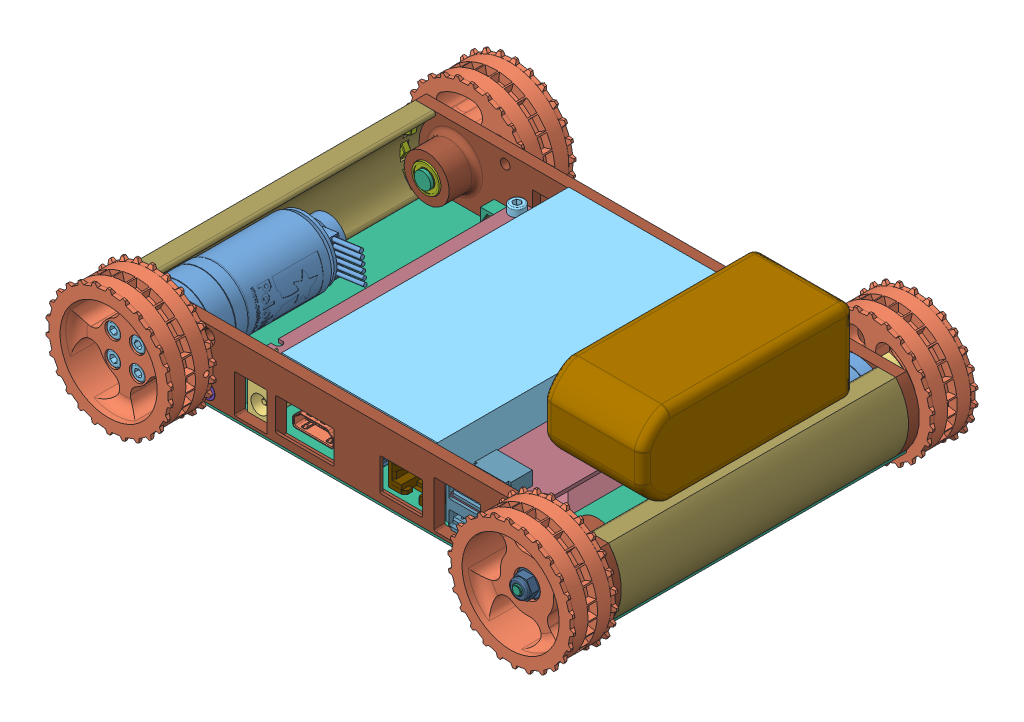
SolidWorks assembly base, configuration Default. Lengths in mm.
Overall size (209.85 74.01 148).
100 component instances, 27 part files, 139 mates.
Components (placement in the parent):
- wheels-1: wheels [Right] at origin size (207.65 62.92 81)
  - wheel-powered-1: wheel-powered [Default] at (0.6984 4.2216 -21.5) x (0.139173 -0.990268 0) z (0 0 1) size (51.92 51.74 81)
    - wheel-motor-1: wheel-motor [Default] at (-36.8745 16.797 -18.375) x (0.990268 -0.139173 0) z (0 0 1) size (25 32.85 72)
    - wheel-body-1: wheel-body [Powered Visual] at (-6.3 12.5 5) x (0.990268 -0.139173 0) z (0 0 1) size (46 45.78 16.5)
    - wheel-motor-mount-1: wheel-motor-mount [Default] at (-6.3 12.5 5) x (0.990268 -0.139173 0) z (-0.139173 -0.990268 0) size (19 5 19)
    - M2.5-6mm-scrub-1: M2.5-6mm-scrub [Default] at (-6.0912 13.9854 7.5) x (0.990268 -0.139173 0) z (0 0 1) size (3.05 6.18 3.38)
    - M3-8mm-bolt-1: M3-8mm-bolt [Default] at (-10.1215 17.5713 15.2) x (1 0 0) z (0 1 0) size (5.5 10.77 5.5)
    - M3-8mm-bolt-2: M3-8mm-bolt [Default] at (-1.2287 16.3215 15.2) x (0.987351 0.158553 0) z (-0.158553 0.987351 0) size (5.5 10.77 5.5)
    - M3-8mm-bolt-4: M3-8mm-bolt [Default] at (-11.3713 8.6785 15.2) x (0.959125 0.282984 0) z (-0.282984 0.959125 0) size (5.5 10.77 5.5)
    - M3-8mm-bolt-6: M3-8mm-bolt [Default] at (-2.4785 7.4287 15.2) x (0.928571 0.371154 0) z (-0.371154 0.928571 0) size (5.5 10.77 5.5)
  - wheel-free-1: wheel-free [Default] at (159.2 12.2 -33.24) x (-0.859884 -0.510489 0) z (0 0 1) size (45.78 46 33.24)
    - wheel-free-shaft-1: wheel-free-shaft [Default] x (1 0 0) z (0 -1 0) size (6 31.32 6)
    - wheel-free-bearing-1: wheel-free-bearing [Default] at (0 0 5.07) x (1 0 0) z (0 1 0) size (10 3.97 10)
    - wheel-free-bearing-2: wheel-free-bearing [Default] at (0 0 15.74) x (0.774434 0.632655 0) z (-0.632655 0.774434 0) size (10 3.97 10)
    - wheel-free-spacer-1: wheel-free-spacer [Default] at (0 0 16.74) x (0.90405 -0.427427 0) z (0.427427 0.90405 0) size (7 1 7)
    - wheel-free-pin-1: wheel-free-pin [Default] at (0 -4.75 18.2) x (0.907276 0 -0.420536) z (0.420536 0 0.907276) size (2 9.5 2)
    - wheel-body-1: wheel-body [Free] at (0 0 16.74) x (0 -1 0) z (0 0 1) size (46 45.78 16.5)
    - M4-nut-1: M4-nut [Default] at (0 0 25.24) x (1 0 0) z (0 -1 0) size (9.3 5.45 9.3)
  - side-plate-1: side-plate [Right] at (12.2 43.075 -21.5) x (0 -1 0) z (0 0 1) size (25 185 14.2)
- wheels-2: wheels [Default] at (171.4 0 -148) x (-1 0 0) z (0 0 -1) size (207.65 62.92 81)
  - wheel-powered-1: wheel-powered [Default] at (0.6984 4.2216 -21.5) x (0.139173 -0.990268 0) z (0 0 1) size (51.92 51.74 81)
    - wheel-motor-1: wheel-motor [Default] at (-36.8745 16.797 -18.375) x (0.990268 -0.139173 0) z (0 0 1) size (25 32.85 72)
    - wheel-body-1: wheel-body [Powered Visual] at (-6.3 12.5 5) x (0.990268 -0.139173 0) z (0 0 1) size (46 45.78 16.5)
    - wheel-motor-mount-1: wheel-motor-mount [Default] at (-6.3 12.5 5) x (0.990268 -0.139173 0) z (-0.139173 -0.990268 0) size (19 5 19)
    - M2.5-6mm-scrub-1: M2.5-6mm-scrub [Default] at (-6.0912 13.9854 7.5) x (0.990268 -0.139173 0) z (0 0 1) size (3.05 6.18 3.38)
    - M3-8mm-bolt-1: M3-8mm-bolt [Default] at (-10.1215 17.5713 15.2) x (1 0 0) z (0 1 0) size (5.5 10.77 5.5)
    - M3-8mm-bolt-2: M3-8mm-bolt [Default] at (-1.2287 16.3215 15.2) x (0.987351 0.158553 0) z (-0.158553 0.987351 0) size (5.5 10.77 5.5)
    - M3-8mm-bolt-4: M3-8mm-bolt [Default] at (-11.3713 8.6785 15.2) x (0.959125 0.282984 0) z (-0.282984 0.959125 0) size (5.5 10.77 5.5)
    - M3-8mm-bolt-6: M3-8mm-bolt [Default] at (-2.4785 7.4287 15.2) x (0.928571 0.371154 0) z (-0.371154 0.928571 0) size (5.5 10.77 5.5)
  - wheel-free-1: wheel-free [Default] at (159.2 12.2 -33.24) x (-0.859884 -0.510489 0) z (0 0 1) size (45.78 46 33.24)
    - wheel-free-shaft-1: wheel-free-shaft [Default] x (1 0 0) z (0 -1 0) size (6 31.32 6)
    - wheel-free-bearing-1: wheel-free-bearing [Default] at (0 0 5.07) x (1 0 0) z (0 1 0) size (10 3.97 10)
    - wheel-free-bearing-2: wheel-free-bearing [Default] at (0 0 15.74) x (0.774434 0.632655 0) z (-0.632655 0.774434 0) size (10 3.97 10)
    - wheel-free-spacer-1: wheel-free-spacer [Default] at (0 0 16.74) x (0.90405 -0.427427 0) z (0.427427 0.90405 0) size (7 1 7)
    - wheel-free-pin-1: wheel-free-pin [Default] at (0 -4.75 18.2) x (0.907276 0 -0.420536) z (0.420536 0 0.907276) size (2 9.5 2)
    - wheel-body-1: wheel-body [Free] at (0 0 16.74) x (0 -1 0) z (0 0 1) size (46 45.78 16.5)
    - M4-nut-1: M4-nut [Default] at (0 0 25.24) x (1 0 0) z (0 -1 0) size (9.3 5.45 9.3)
  - side-plate-1: side-plate [Default] at (12.2 43.075 -21.5) x (0 -1 0) z (0 0 1) size (25 185 14.2)
- base-end-1: base-end [Default] at (159.2 43.075 -126.5) x (0 1 0) z (0 0 1) size (25 12.02 105)
- base-end-2: base-end [Default] at (12.2 -18.675 -126.5) x (0 -1 0) z (0 0 1) size (25 12.02 105)
- computer-2: computer [Default] at (85.7 11.95 -74) x (0 0 -1) z (-1 0 0) size (112.78 24.5 100)
  - computer-pcb-1: computer-pcb [Default] at origin size (109 1.25 100)
  - usb-a-double-1: usb-a-double [Default] at (47.745 -3.9 -36.45) x (0 0 -1) z (1 0 0) size (14.6 16.2 17.65)
  - audio-jack-1: audio-jack [Défaut] at (56.5 1.25 -19.25) x (-1 0 0) z (0 0 -1) size (15 6 12)
    - mj1-3510-smt_01-1: mj1-3510-smt_01 [Défaut] at origin size (15 6 10.5)
    - mj1-3510-smt_02-1: mj1-3510-smt_02 [Défaut] at origin size (1 0.25 2.25)
    - mj1-3510-smt_03-1: mj1-3510-smt_03 [Défaut] at origin size (1.5 0.25 2.25)
  - usb-a-double-2: usb-a-double [Default] at (-44.375 -3.9 -36.45) x (0 0 1) z (-1 0 0) size (14.6 16.2 17.65)
  - ethernet-jack-1: ethernet-jack [Default] at (-45.057 -4.375 -15.993) x (0 0 1) z (-1 0 0) size (15.99 16.55 21.05)
  - mini-display-port-1: mini-display-port [Default] at (-52.62 -3.25 -3.4195) x (0 0 1) z (-1 0 0) size (9.11 10.68 14.44)
  - hdmi-1: hdmi [Default] at (-44.9 4.575 19.5) x (0 0 1) z (-1 0 0) size (16.2 8 9.9)
  - power-jack-1: power-jack [Default] at (-45.5 -0.05 39) x (0 0 -1) z (1 0 0) size (9.4 14.5 14.4)
  - computer-top-components-1: computer-top-components [Default] at (3.5 1.25 -0.5) size (74 10 95)
  - computer-bottom-components-1: computer-bottom-components [Default] at (0 -13.25 3.227) x (0 0 1) z (-1 0 0) size (57 13.25 105)
- bottom-plate-1: bottom-plate [Default] at (12.2 -0.3 -21.5) x (0 0 -1) z (0 -1 0) size (113 175.62 11.8)
- M3-nut-1: M3-nut [Default] at (174.2 12.2 -27.85) x (-0.866025 0.5 0) z (0.5 0.866025 0) size (5.5 2.61 6.23)
- M3-flathead-bolt-1: M3-flathead-bolt [Default] at (174.2 12.2 -17.5) x (0.99991 -0.013402 0) z (0.013402 0.99991 0) size (5.5 10.3 5.5)
- M3-nut-2: M3-nut [Default] at (171.4873 20.8036 -27.85) x (-0.996195 -0.087156 0) z (-0.087156 0.996195 0) size (5.5 2.61 6.23)
- M3-nut-4: M3-nut [Default] at (171.4873 3.5964 -27.85) x (-0.422618 0.906308 0) z (0.906308 0.422618 0) size (5.5 2.61 6.23)
- M3-nut-6: M3-nut [Default] at (171.4873 20.8036 -120.15) x (0.422618 0.906308 0) z (-0.906308 0.422618 0) size (5.5 2.61 6.23)
- M3-nut-8: M3-nut [Default] at (174.2 12.2 -120.15) x (0.866025 0.5 0) z (-0.5 0.866025 0) size (5.5 2.61 6.23)
- M3-nut-10: M3-nut [Default] at (171.4873 3.5964 -120.15) x (0.996195 -0.087156 0) z (0.087156 0.996195 0) size (5.5 2.61 6.23)
- M3-nut-12: M3-nut [Default] at (-0.0873 20.8036 -120.15) x (0.996195 -0.087156 0) z (0.087156 0.996195 0) size (5.5 2.61 6.23)
- M3-nut-14: M3-nut [Default] at (-2.8 12.2 -120.15) x (0.866025 0.5 0) z (-0.5 0.866025 0) size (5.5 2.61 6.23)
- M3-nut-16: M3-nut [Default] at (-0.0873 3.5964 -120.15) x (0.422618 0.906308 0) z (-0.906308 0.422618 0) size (5.5 2.61 6.23)
- M3-nut-18: M3-nut [Default] at (-0.0873 20.8036 -27.85) x (-0.422618 0.906308 0) z (0.906308 0.422618 0) size (5.5 2.61 6.23)
- M3-nut-20: M3-nut [Default] at (-2.8 12.2 -27.85) x (-0.866025 0.5 0) z (0.5 0.866025 0) size (5.5 2.61 6.23)
- M3-nut-22: M3-nut [Default] at (-0.0873 3.5964 -27.85) x (-0.996195 -0.087156 0) z (-0.087156 0.996195 0) size (5.5 2.61 6.23)
- M3-flathead-bolt-2: M3-flathead-bolt [Default] at (171.4873 20.8036 -17.5) x (0.203723 -0.979029 0) z (0.979029 0.203723 0) size (5.5 10.3 5.5)
- M3-flathead-bolt-4: M3-flathead-bolt [Default] at (171.4873 3.5964 -17.5) x (0.030622 -0.999531 0) z (0.999531 0.030622 0) size (5.5 10.3 5.5)
- M3-flathead-bolt-6: M3-flathead-bolt [Default] at (-0.0873 20.8036 -17.5) x (-0.14341 -0.989663 0) z (0.989663 -0.14341 0) size (5.5 10.3 5.5)
- M3-flathead-bolt-8: M3-flathead-bolt [Default] at (-2.8 12.2 -17.5) x (-0.313085 -0.949725 0) z (0.949725 -0.313085 0) size (5.5 10.3 5.5)
- M3-flathead-bolt-10: M3-flathead-bolt [Default] at (-0.0873 3.5964 -17.5) x (-0.473246 -0.88093 0) z (0.88093 -0.473246 0) size (5.5 10.3 5.5)
- M3-flathead-bolt-12: M3-flathead-bolt [Default] at (-0.0873 20.8036 -130.5) x (0.999996 0.002801 0) z (0.002801 -0.999996 0) size (5.5 10.3 5.5)
- M3-flathead-bolt-14: M3-flathead-bolt [Default] at (-2.8 12.2 -130.5) x (0.995351 0.096317 0) z (0.096317 -0.995351 0) size (5.5 10.3 5.5)
- M3-flathead-bolt-16: M3-flathead-bolt [Default] at (-0.0873 3.5964 -130.5) x (0.972009 0.234946 0) z (0.234946 -0.972009 0) size (5.5 10.3 5.5)
- M3-flathead-bolt-18: M3-flathead-bolt [Default] at (171.4873 20.8036 -130.5) x (0.918511 0.395394 0) z (0.395394 -0.918511 0) size (5.5 10.3 5.5)
- M3-flathead-bolt-20: M3-flathead-bolt [Default] at (174.2 12.2 -130.5) x (0.83874 0.544533 0) z (0.544533 -0.83874 0) size (5.5 10.3 5.5)
- M3-flathead-bolt-22: M3-flathead-bolt [Default] at (171.4873 3.5964 -130.5) x (0.754091 0.65677 0) z (0.65677 -0.754091 0) size (5.5 10.3 5.5)
- M3-flathead-bolt-24: M3-flathead-bolt [Default] at (167.7 12.2 -130.5) x (0.689358 0.724421 0) z (0.724421 -0.689358 0) size (5.5 10.3 5.5)
- M3-flathead-bolt-26: M3-flathead-bolt [Default] at (150.7 12.2 -130.5) x (0.659275 0.751902 0) z (0.751902 -0.659275 0) size (5.5 10.3 5.5)
- M3-flathead-bolt-28: M3-flathead-bolt [Default] at (20.7 12.2 -17.5) x (-0.88093 0.473246 0) z (-0.473246 -0.88093 0) size (5.5 10.3 5.5)
- M3-flathead-bolt-30: M3-flathead-bolt [Default] at (3.7 12.2 -17.5) x (-0.785369 0.619029 0) z (-0.619029 -0.785369 0) size (5.5 10.3 5.5)
- M3-flathead-bolt-32: M3-flathead-bolt [Default] at (30.7 3.5964 -17.5) x (-0.665944 0.746002 0) z (-0.746002 -0.665944 0) size (5.5 10.3 5.5)
- M3-flathead-bolt-34: M3-flathead-bolt [Default] at (140.7 3.5964 -17.5) x (-0.526285 0.850308 0) z (-0.850308 -0.526285 0) size (5.5 10.3 5.5)
- M3-flathead-bolt-36: M3-flathead-bolt [Default] at (30.7 3.5964 -130.5) x (0.918511 0.395394 0) z (0.395394 -0.918511 0) size (5.5 10.3 5.5)
- M3-flathead-bolt-38: M3-flathead-bolt [Default] at (140.7 3.5964 -130.5) x (0.976622 0.214965 0) z (0.214965 -0.976622 0) size (5.5 10.3 5.5)
- M3-nut-24: M3-nut [Default] at (39.05 0.85 -28.7) size (5.5 2.61 6.23)
- M3-nut-25: M3-nut [Default] at (39.05 0.85 -122.5) x (-1 0 0) z (0 0 -1) size (5.5 2.61 6.23)
- M3-nut-27: M3-nut [Default] at (132.35 0.85 -122.5) x (-1 0 0) z (0 0 -1) size (5.5 2.61 6.23)
- M3-nut-29: M3-nut [Default] at (132.35 0.85 -28.7) x (-1 0 0) z (0 0 -1) size (5.5 2.61 6.23)
- M3-8mm-bolt-1: M3-8mm-bolt [Default] at (132.35 14.9 -28.7) x (-0.837169 0 -0.546944) z (-0.546944 0 0.837169) size (5.5 10.77 5.5)
- M3-8mm-bolt-2: M3-8mm-bolt [Default] at (39.05 14.9 -28.7) x (-0.925243 0 -0.379375) z (-0.379375 0 0.925243) size (5.5 10.77 5.5)
- M3-8mm-bolt-3: M3-8mm-bolt [Default] at (39.05 14.9 -122.5) x (-0.985271 0 -0.170998) z (-0.170998 0 0.985271) size (5.5 10.77 5.5)
- M3-8mm-bolt-4: M3-8mm-bolt [Default] at (132.35 14.9 -122.5) x (-0.997902 0 0.064746) z (0.064746 0 0.997902) size (5.5 10.77 5.5)
- M3-nut-30: M3-nut [Default] at (30.7 3.5964 -121.65) x (0 1 0) z (-1 0 0) size (5.5 2.61 6.23)
- M3-nut-31: M3-nut [Default] at (140.7 3.5964 -124) x (0.866025 -0.5 0) z (-0.5 -0.866025 0) size (5.5 2.61 6.23)
- M3-nut-33: M3-nut [Default] at (140.7 3.5964 -26.35) x (0 1 0) z (1 0 0) size (5.5 2.61 6.23)
- M3-nut-35: M3-nut [Default] at (30.7 3.5964 -24) x (-0.866025 -0.5 0) z (0.5 -0.866025 0) size (5.5 2.61 6.23)
- battery-1: battery [Default] at (153.9032 24.7 -74) x (0 0 -1) z (1 0 0) size (77.55 30.1 36.52)
Mates (geometry in assembly coordinates):
- Concentric2: concentric anti-aligned: cylinder of wheels-1/wheel-powered-1/wheel-body-1 through (12.2 12.2 0) axis (0 0 -1) radius 21.75; cylinder of wheels-2/wheel-free-1/wheel-body-1 through (12.2 12.2 -148) axis (0 0 1) radius 21.75
- Concentric3: concentric anti-aligned: cylinder of wheels-1/wheel-free-1/wheel-body-1 through (159.2 12.2 0) axis (0 0 -1) radius 21.75; cylinder of wheels-2/wheel-powered-1/wheel-body-1 through (159.2 12.2 -148) axis (0 0 1) radius 21.75
- InPlace1: in place: plane of ? through (157.2 43.075 -126.5) normal (0 0 1); plane of ? through (0 0 -126.5) normal (0 0 1); moOrthogonalPlaneRef_w of ? through (157.2 43.075 -126.5) normal (0 0 1); plane of ? through (0 0 -126.5) normal (0 1 0); plane of ? through (157.2 43.075 -126.5) normal (0 0 1); plane of ? through (0 0 -126.5) normal (1 0 0); plane of wheels-2/side-plate-1 through (159.2 43.075 -126.5) normal (0 0 1); unknown of base-end-1
- Coincident4: coincident aligned: plane of wheels-2/side-plate-1; plane of base-end-1
- Coincident5: coincident aligned: moOrthogonalPlaneRef_w of wheels-2/side-plate-1 through (159.2 43.075 -126.5) normal (-1 0 0); plane of base-end-1
- Coincident6: coincident anti-aligned: moOrthogonalPlaneRef_w of wheels-2/side-plate-1 through (159.2 43.075 -126.5) normal (0 -1 0); plane of base-end-1
- Coincident7: coincident anti-aligned: plane of wheels-1/side-plate-1 through (12.2 43.075 -21.5) normal (0 0 -1); plane of base-end-2 through (159.2 -18.675 -21.5) normal (0 0 1)
- Concentric4: concentric anti-aligned: circle of wheels-1/side-plate-1; circle of base-end-2
- Coincident9: coincident aligned: plane of wheels-1/side-plate-1 through (12.2 24.7 -17.5) normal (0 1 0); plane of wheels-2/side-plate-1 through (159.2 24.7 -130.5) normal (0 1 0)
- InPlace2: in place: plane of wheels-1/side-plate-1 through (12.2 -0.3 -17.5) normal (0 -1 0); plane of ? through (0 -0.3 0) normal (0 -1 0); plane of wheels-1/side-plate-1 through (12.2 -0.3 -17.5) normal (0 -1 0); unknown of ?; plane of wheels-1/side-plate-1 through (12.2 -0.3 -17.5) normal (0 -1 0); unknown of ?; plane of wheels-1/side-plate-1 through (12.2 -0.3 -17.5) normal (0 -1 0); unknown of bottom-plate-1
- Coincident10: coincident aligned: plane of ?; plane of bottom-plate-1
- Coincident11: coincident aligned: moOrthogonalPlaneRef_w of wheels-1/side-plate-1 through (12.2 -0.3 -21.5) normal (1 0 0); plane of bottom-plate-1
- Coincident12: coincident anti-aligned: moOrthogonalPlaneRef_w of wheels-1/side-plate-1 through (12.2 -0.3 -21.5) normal (0 0 1); plane of bottom-plate-1
- Width1: width anti-aligned: plane of bottom-plate-1 through (173.5091 -1.1 -130.5) normal (0 0 -1); plane of bottom-plate-1 through (173.5091 -1.1 -17.5) normal (0 0 1); plane of computer-2/computer-pcb-1 through (85.7 10.7 -21.5) normal (0 0 1); plane of computer-2/computer-pcb-1 through (85.7 10.7 -126.5) normal (0 0 -1)
- Width2: width anti-aligned: plane of bottom-plate-1 through (173.5091 -1.1 -130.5) normal (1 0 0); plane of bottom-plate-1 through (-2.1091 -1.1 -130.5) normal (-1 0 0); plane of computer-2/computer-pcb-1 through (35.7 10.7 -74) normal (-1 0 0); plane of computer-2/computer-pcb-1 through (135.7 10.7 -74) normal (1 0 0)
- Distance4: distance = 1 mm anti-aligned: plane of computer-2/computer-top-components-1 through (86.2 0.7 -77.5) normal (0 -1 0); plane of bottom-plate-1 through (12.2 -0.3 -21.5) normal (0 1 0)
- Coincident11: coincident anti-aligned: plane of base-end-1 through (159.2 43.075 -25.5) normal (0 0 -1); plane of M3-nut-1 through (174.2 12.2 -25.5) normal (0 0 1)
- Concentric5: concentric anti-aligned: circle of wheels-1/side-plate-1; circle of M3-nut-1
- Parallel1: parallel anti-aligned: plane of base-end-1 through (159.2 9.35 -28.5) normal (0 1 0); plane of M3-nut-1 through (172.6123 9.45 -25.5) normal (0 -1 0)
- Concentric6: concentric anti-aligned: circle of wheels-1/side-plate-1; circle of M3-flathead-bolt-1
- Coincident14: coincident aligned: plane of wheels-1/side-plate-1 through (12.2 43.075 -17.5) normal (0 0 1); plane of M3-flathead-bolt-1 through (174.2 12.2 -17.5) normal (0 0 1)
- Coincident15: coincident anti-aligned: plane of base-end-1 through (159.2 43.075 -25.5) normal (0 0 -1); plane of M3-nut-2 through (171.4873 20.8036 -25.5) normal (0 0 1)
- Concentric9: concentric anti-aligned: circle of wheels-1/side-plate-1; circle of M3-nut-2
- Parallel2: parallel anti-aligned: plane of base-end-1 through (175.3412 20.023 -28.5) normal (-0.573576 0.819152 0); plane of M3-nut-2 through (171.764 17.6403 -25.5) normal (0.573576 -0.819152 0)
- Coincident16: coincident anti-aligned: plane of base-end-1 through (159.2 43.075 -25.5) normal (0 0 -1); plane of M3-nut-4 through (171.4873 3.5964 -25.5) normal (0 0 1)
- Concentric10: concentric anti-aligned: circle of wheels-1/side-plate-1; circle of M3-nut-4
- Parallel3: parallel anti-aligned: plane of base-end-1 through (143.0588 20.023 -28.5) normal (0.573576 0.819152 0); plane of M3-nut-4 through (168.6094 2.2544 -25.5) normal (-0.573576 -0.819152 0)
- Coincident17: coincident anti-aligned: plane of base-end-1 through (159.2 43.075 -122.5) normal (0 0 1); plane of M3-nut-6 through (171.4873 20.8036 -122.5) normal (0 0 -1)
- Concentric11: concentric anti-aligned: circle of base-end-1; circle of M3-nut-6
- Parallel4: parallel anti-aligned: plane of base-end-1 through (175.3412 20.023 -119.5) normal (-0.573576 0.819152 0); plane of M3-nut-6 through (174.3652 19.4617 -122.5) normal (0.573576 -0.819152 0)
- Coincident18: coincident anti-aligned: plane of base-end-1 through (159.2 43.075 -122.5) normal (0 0 1); plane of M3-nut-8 through (174.2 12.2 -122.5) normal (0 0 -1)
- Concentric12: concentric anti-aligned: circle of base-end-1; circle of M3-nut-8
- Parallel5: parallel anti-aligned: plane of base-end-1 through (159.2 9.35 -119.5) normal (0 1 0); plane of M3-nut-8 through (175.7877 9.45 -122.5) normal (0 -1 0)
- Coincident19: coincident anti-aligned: plane of base-end-1 through (159.2 43.075 -122.5) normal (0 0 1); plane of M3-nut-10 through (171.4873 3.5964 -122.5) normal (0 0 -1)
- Concentric13: concentric anti-aligned: circle of base-end-1; circle of M3-nut-10
- Parallel6: parallel anti-aligned: plane of base-end-1 through (143.0588 20.023 -119.5) normal (0.573576 0.819152 0); plane of M3-nut-10 through (171.2105 0.433 -122.5) normal (-0.573576 -0.819152 0)
- Coincident20: coincident anti-aligned: plane of base-end-2 through (12.2 -18.675 -122.5) normal (0 0 1); plane of M3-nut-12 through (-0.0873 20.8036 -122.5) normal (0 0 -1)
- Concentric14: concentric aligned: circle of base-end-2; circle of M3-nut-12
- Parallel7: parallel anti-aligned: plane of base-end-2 through (25.0718 -0.2921 -119.5) normal (0.573576 0.819152 0); plane of M3-nut-12 through (-0.364 17.6403 -122.5) normal (-0.573576 -0.819152 0)
- Coincident21: coincident anti-aligned: plane of base-end-2 through (12.2 -18.675 -122.5) normal (0 0 1); plane of M3-nut-14 through (-2.8 12.2 -122.5) normal (0 0 -1)
- Concentric15: concentric aligned: circle of base-end-2; circle of M3-nut-14
- Parallel8: parallel anti-aligned: plane of base-end-2 through (12.2 9.35 -119.5) normal (0 1 0); plane of M3-nut-14 through (-1.2123 9.45 -122.5) normal (0 -1 0)
- Coincident22: coincident anti-aligned: plane of base-end-2 through (12.2 -18.675 -122.5) normal (0 0 1); plane of M3-nut-16 through (-0.0873 3.5964 -122.5) normal (0 0 -1)
- Concentric16: concentric aligned: circle of base-end-2; circle of M3-nut-16
- Parallel9: parallel anti-aligned: plane of base-end-2 through (-0.6718 -0.2921 -119.5) normal (-0.573576 0.819152 0); plane of M3-nut-16 through (2.7906 2.2544 -122.5) normal (0.573576 -0.819152 0)
- Coincident23: coincident anti-aligned: plane of base-end-2 through (12.2 -18.675 -25.5) normal (0 0 -1); plane of M3-nut-18 through (-0.0873 20.8036 -25.5) normal (0 0 1)
- Concentric17: concentric anti-aligned: circle of base-end-2; circle of M3-nut-18
- Parallel10: parallel anti-aligned: plane of base-end-2 through (25.0718 -0.2921 -28.5) normal (0.573576 0.819152 0); plane of M3-nut-18 through (-2.9652 19.4617 -25.5) normal (-0.573576 -0.819152 0)
- Coincident24: coincident anti-aligned: plane of base-end-2 through (12.2 -18.675 -25.5) normal (0 0 -1); plane of M3-nut-20 through (-2.8 12.2 -25.5) normal (0 0 1)
- Concentric18: concentric anti-aligned: circle of base-end-2; circle of M3-nut-20
- Parallel11: parallel anti-aligned: plane of base-end-2 through (12.2 9.35 -28.5) normal (0 1 0); plane of M3-nut-20 through (-4.3877 9.45 -25.5) normal (0 -1 0)
- Coincident25: coincident anti-aligned: plane of base-end-2 through (12.2 -18.675 -25.5) normal (0 0 -1); plane of M3-nut-22 through (-0.0873 3.5964 -25.5) normal (0 0 1)
- Concentric19: concentric anti-aligned: circle of base-end-2; circle of M3-nut-22
- Parallel12: parallel anti-aligned: plane of base-end-2 through (-0.6718 -0.2921 -28.5) normal (-0.573576 0.819152 0); plane of M3-nut-22 through (0.1895 0.433 -25.5) normal (0.573576 -0.819152 0)
- Concentric20: concentric aligned: circle of wheels-1/side-plate-1; circle of M3-flathead-bolt-2
- Coincident26: coincident aligned: plane of wheels-1/side-plate-1 through (12.2 43.075 -17.5) normal (0 0 1); plane of M3-flathead-bolt-2 through (171.4873 20.8036 -17.5) normal (0 0 1)
- Concentric21: concentric aligned: circle of wheels-1/side-plate-1; circle of M3-flathead-bolt-4
- Coincident27: coincident aligned: plane of wheels-1/side-plate-1 through (12.2 43.075 -17.5) normal (0 0 1); plane of M3-flathead-bolt-4 through (171.4873 3.5964 -17.5) normal (0 0 1)
- Concentric22: concentric aligned: circle of wheels-1/side-plate-1; circle of M3-flathead-bolt-6
- Coincident28: coincident aligned: plane of wheels-1/side-plate-1 through (12.2 43.075 -17.5) normal (0 0 1); plane of M3-flathead-bolt-6 through (-0.0873 20.8036 -17.5) normal (0 0 1)
- Concentric23: concentric aligned: circle of wheels-1/side-plate-1; circle of M3-flathead-bolt-8
- Coincident29: coincident aligned: plane of wheels-1/side-plate-1 through (12.2 43.075 -17.5) normal (0 0 1); plane of M3-flathead-bolt-8 through (-2.8 12.2 -17.5) normal (0 0 1)
- Concentric24: concentric aligned: circle of wheels-1/side-plate-1; circle of M3-flathead-bolt-10
- Coincident30: coincident aligned: plane of wheels-1/side-plate-1 through (12.2 43.075 -17.5) normal (0 0 1); plane of M3-flathead-bolt-10 through (-0.0873 3.5964 -17.5) normal (0 0 1)
- Concentric25: concentric aligned: circle of wheels-2/side-plate-1; circle of M3-flathead-bolt-12
- Coincident31: coincident aligned: plane of wheels-2/side-plate-1 through (159.2 43.075 -130.5) normal (0 0 -1); plane of M3-flathead-bolt-12 through (-0.0873 20.8036 -130.5) normal (0 0 -1)
- Concentric26: concentric aligned: circle of wheels-2/side-plate-1; circle of M3-flathead-bolt-14
- Coincident32: coincident aligned: plane of wheels-2/side-plate-1 through (159.2 43.075 -130.5) normal (0 0 -1); plane of M3-flathead-bolt-14 through (-2.8 12.2 -130.5) normal (0 0 -1)
- Concentric27: concentric aligned: circle of wheels-2/side-plate-1; circle of M3-flathead-bolt-16
- Coincident33: coincident aligned: plane of wheels-2/side-plate-1 through (159.2 43.075 -130.5) normal (0 0 -1); plane of M3-flathead-bolt-16 through (-0.0873 3.5964 -130.5) normal (0 0 -1)
- Concentric28: concentric aligned: circle of wheels-2/side-plate-1; circle of M3-flathead-bolt-18
- Coincident34: coincident aligned: plane of wheels-2/side-plate-1 through (159.2 43.075 -130.5) normal (0 0 -1); plane of M3-flathead-bolt-18 through (171.4873 20.8036 -130.5) normal (0 0 -1)
- Concentric29: concentric aligned: circle of wheels-2/side-plate-1; circle of M3-flathead-bolt-20
- Coincident35: coincident aligned: plane of wheels-2/side-plate-1 through (159.2 43.075 -130.5) normal (0 0 -1); plane of M3-flathead-bolt-20 through (174.2 12.2 -130.5) normal (0 0 -1)
- Concentric30: concentric aligned: circle of wheels-2/side-plate-1; circle of M3-flathead-bolt-22
- Coincident36: coincident aligned: plane of wheels-2/side-plate-1 through (159.2 43.075 -130.5) normal (0 0 -1); plane of M3-flathead-bolt-22 through (171.4873 3.5964 -130.5) normal (0 0 -1)
- Concentric31: concentric aligned: circle of wheels-2/side-plate-1; circle of M3-flathead-bolt-24
- Coincident37: coincident aligned: plane of wheels-2/side-plate-1 through (159.2 43.075 -130.5) normal (0 0 -1); plane of M3-flathead-bolt-24 through (167.7 12.2 -130.5) normal (0 0 -1)
- Concentric32: concentric aligned: circle of wheels-2/side-plate-1; circle of M3-flathead-bolt-26
- Coincident38: coincident aligned: plane of wheels-2/side-plate-1 through (159.2 43.075 -130.5) normal (0 0 -1); plane of M3-flathead-bolt-26 through (150.7 12.2 -130.5) normal (0 0 -1)
- Concentric33: concentric aligned: circle of wheels-1/side-plate-1; circle of M3-flathead-bolt-28
- Coincident39: coincident aligned: plane of wheels-1/side-plate-1 through (12.2 43.075 -17.5) normal (0 0 1); plane of M3-flathead-bolt-28 through (20.7 12.2 -17.5) normal (0 0 1)
- Concentric34: concentric aligned: circle of wheels-1/side-plate-1; circle of M3-flathead-bolt-30
- Coincident40: coincident aligned: plane of wheels-1/side-plate-1 through (12.2 43.075 -17.5) normal (0 0 1); plane of M3-flathead-bolt-30 through (3.7 12.2 -17.5) normal (0 0 1)
- Concentric35: concentric aligned: circle of wheels-1/side-plate-1; circle of M3-flathead-bolt-32
- Coincident41: coincident aligned: plane of wheels-1/side-plate-1 through (12.2 43.075 -17.5) normal (0 0 1); plane of M3-flathead-bolt-32 through (30.7 3.5964 -17.5) normal (0 0 1)
- Concentric36: concentric aligned: circle of wheels-1/side-plate-1; circle of M3-flathead-bolt-34
- Coincident42: coincident aligned: plane of wheels-1/side-plate-1 through (12.2 43.075 -17.5) normal (0 0 1); plane of M3-flathead-bolt-34 through (140.7 3.5964 -17.5) normal (0 0 1)
- Concentric37: concentric aligned: circle of wheels-2/side-plate-1; circle of M3-flathead-bolt-36
- Coincident43: coincident aligned: plane of wheels-2/side-plate-1 through (159.2 43.075 -130.5) normal (0 0 -1); plane of M3-flathead-bolt-36 through (30.7 3.5964 -130.5) normal (0 0 -1)
- Concentric38: concentric aligned: circle of wheels-2/side-plate-1; circle of M3-flathead-bolt-38
- Coincident44: coincident aligned: plane of wheels-2/side-plate-1 through (159.2 43.075 -130.5) normal (0 0 -1); plane of M3-flathead-bolt-38 through (140.7 3.5964 -130.5) normal (0 0 -1)
- Coincident45: coincident anti-aligned: plane of bottom-plate-1 through (12.2 3.2 -21.5) normal (0 -1 0); plane of M3-nut-24 through (39.05 3.2 -28.7) normal (0 1 0)
- Concentric39: concentric anti-aligned: circle of bottom-plate-1; circle of M3-nut-24
- Parallel13: parallel anti-aligned: plane of bottom-plate-1 through (42.05 3.2 -21.5) normal (-1 0 0); plane of M3-nut-24 through (41.8 3.2 -27.1123) normal (1 0 0)
- Coincident47: coincident anti-aligned: plane of bottom-plate-1 through (12.2 3.2 -21.5) normal (0 -1 0); plane of M3-nut-25 through (39.05 3.2 -122.5) normal (0 1 0)
- Concentric40: concentric anti-aligned: circle of bottom-plate-1; circle of M3-nut-25
- Parallel14: parallel aligned: plane of M3-nut-25 through (36.3 3.2 -124.0877) normal (-1 0 0); plane of bottom-plate-1 through (42.05 3.2 -21.5) normal (-1 0 0)
- Coincident48: coincident anti-aligned: plane of bottom-plate-1 through (12.2 3.2 -21.5) normal (0 -1 0); plane of M3-nut-27 through (132.35 3.2 -122.5) normal (0 1 0)
- Concentric41: concentric aligned: circle of M3-nut-27; circle of bottom-plate-1
- Parallel15: parallel anti-aligned: plane of M3-nut-27 through (129.6 3.2 -124.0877) normal (-1 0 0); plane of bottom-plate-1 through (129.35 3.2 -21.5) normal (1 0 0)
- Coincident49: coincident anti-aligned: plane of bottom-plate-1 through (12.2 3.2 -21.5) normal (0 -1 0); plane of M3-nut-29 through (132.35 3.2 -28.7) normal (0 1 0)
- Concentric42: concentric anti-aligned: circle of bottom-plate-1; circle of M3-nut-29
- Parallel16: parallel anti-aligned: plane of bottom-plate-1 through (129.35 3.2 -21.5) normal (1 0 0); plane of M3-nut-29 through (129.6 3.2 -30.2877) normal (-1 0 0)
- Coincident50: coincident anti-aligned: plane of computer-2/computer-pcb-1 through (85.7 11.95 -74) normal (0 1 0); plane of M3-8mm-bolt-1 through (132.35 11.95 -28.7) normal (0 -1 0)
- Concentric43: concentric anti-aligned: cylinder of computer-2/computer-pcb-1 through (132.35 11.951 -28.7) axis (0 -1 0) radius 2; cylinder of M3-8mm-bolt-1 through (132.35 11.95 -28.7) axis (0 1 0) radius 2.75
- Coincident51: coincident anti-aligned: plane of computer-2/computer-pcb-1 through (85.7 11.95 -74) normal (0 1 0); plane of M3-8mm-bolt-2 through (39.05 11.95 -28.7) normal (0 -1 0)
- Concentric44: concentric anti-aligned: cylinder of computer-2/computer-pcb-1 through (39.05 11.951 -28.7) axis (0 -1 0) radius 2; cylinder of M3-8mm-bolt-2 through (39.05 11.95 -28.7) axis (0 1 0) radius 2.75
- Coincident52: coincident anti-aligned: plane of computer-2/computer-pcb-1 through (85.7 11.95 -74) normal (0 1 0); plane of M3-8mm-bolt-3 through (39.05 11.95 -122.5) normal (0 -1 0)
- Concentric45: concentric anti-aligned: cylinder of computer-2/computer-pcb-1 through (39.05 11.951 -122.5) axis (0 -1 0) radius 2; cylinder of M3-8mm-bolt-3 through (39.05 11.95 -122.5) axis (0 1 0) radius 2.75
- Coincident53: coincident anti-aligned: plane of computer-2/computer-pcb-1 through (85.7 11.95 -74) normal (0 1 0); plane of M3-8mm-bolt-4 through (132.35 11.95 -122.5) normal (0 -1 0)
- Concentric46: concentric anti-aligned: cylinder of computer-2/computer-pcb-1 through (132.35 11.951 -122.5) axis (0 -1 0) radius 2; cylinder of M3-8mm-bolt-4 through (132.35 11.95 -122.5) axis (0 1 0) radius 2.75
- Coincident54: coincident anti-aligned: plane of bottom-plate-1 through (12.2 -0.3 -124) normal (0 0 1); plane of M3-nut-30 through (30.7 3.5964 -124) normal (0 0 -1)
- Concentric47: concentric aligned: circle of bottom-plate-1; circle of M3-nut-30
- Parallel17: parallel anti-aligned: plane of bottom-plate-1 through (27.2359 3.5964 -124) normal (0.866025 0.5 0); plane of M3-nut-30 through (29.1123 0.8464 -124) normal (-0.866025 -0.5 0)
- Concentric48: concentric anti-aligned: circle of M3-nut-31; circle of bottom-plate-1
- Parallel18: parallel anti-aligned: plane of M3-nut-31 through (137.5246 3.5964 -121.65) normal (-0.866025 -0.5 0); plane of bottom-plate-1 through (138.9679 0.5964 -124) normal (0.866025 0.5 0)
- Coincident57: coincident anti-aligned: plane of bottom-plate-1 through (12.2 -0.3 -24) normal (0 0 -1); plane of M3-nut-33 through (140.7 3.5964 -24) normal (0 0 1)
- Concentric49: concentric aligned: circle of M3-nut-33; circle of bottom-plate-1
- Parallel19: parallel anti-aligned: plane of M3-nut-33 through (142.2877 0.8464 -24) normal (0.866025 -0.5 0); plane of bottom-plate-1 through (144.1641 3.5964 -24) normal (-0.866025 0.5 0)
- Concentric50: concentric aligned: circle of M3-nut-35; circle of bottom-plate-1
- Parallel20: parallel anti-aligned: plane of M3-nut-35 through (33.8754 3.5964 -26.35) normal (0.866025 -0.5 0); plane of bottom-plate-1 through (32.4321 0.5964 -24) normal (-0.866025 0.5 0)
- Coincident59: coincident anti-aligned: plane of bottom-plate-1 through (12.2 -0.3 -124) normal (0 0 1); plane of M3-nut-31 through (140.7 3.5964 -124) normal (0 0 -1)
- Coincident60: coincident anti-aligned: plane of bottom-plate-1 through (12.2 -0.3 -24) normal (0 0 -1); plane of M3-nut-35 through (30.7 3.5964 -24) normal (0 0 1)
- Distance5: distance = 148 mm anti-aligned: plane of wheels-1/wheel-free-1/wheel-body-1 through (159.2 12.2 0) normal (0 0 1); plane of wheels-2/wheel-powered-1/wheel-body-1 through (159.2 12.2 -148) normal (0 0 -1)
- Coincident62: coincident anti-aligned: plane of wheels-2/side-plate-1 through (159.2 22.2 -126.5) normal (0 -1 0); plane of ? through (30.7 22.2 -122.5) normal (0 1 0)
- Concentric51: concentric anti-aligned: circle of wheels-2/side-plate-1; circle of ?
- Parallel21: parallel anti-aligned: plane of wheels-2/side-plate-1 through (33.7 19.7 -126.5) normal (-1 0 0); plane of ? through (33.45 22.2 -120.9123) normal (1 0 0)
- Coincident64: coincident anti-aligned: plane of wheels-2/side-plate-1 through (159.2 22.2 -126.5) normal (0 -1 0); plane of ? through (140.7 22.2 -122.5) normal (0 1 0)
- Concentric52: concentric aligned: circle of wheels-2/side-plate-1; circle of ?
- Parallel22: parallel anti-aligned: plane of wheels-2/side-plate-1 through (137.7 19.7 -126.5) normal (1 0 0); plane of ? through (137.95 22.2 -124.0877) normal (-1 0 0)
- Coincident65: coincident anti-aligned: plane of wheels-1/side-plate-1 through (159.2 22.2 -21.5) normal (0 -1 0); plane of ? through (30.7 22.2 -25.5) normal (0 1 0)
- Concentric53: concentric aligned: circle of wheels-1/side-plate-1; circle of ?
- Parallel23: parallel anti-aligned: plane of wheels-1/side-plate-1 through (27.7 19.7 -21.5) normal (1 0 0); plane of ? through (27.95 22.2 -27.0877) normal (-1 0 0)
- Coincident66: coincident anti-aligned: plane of wheels-2/side-plate-1 through (159.2 22.2 -126.5) normal (0 -1 0); plane of ? through (140.7 22.2 -25.5) normal (0 1 0)
- Concentric54: concentric anti-aligned: circle of wheels-1/side-plate-1; circle of ?
- Parallel24: parallel anti-aligned: plane of wheels-1/side-plate-1 through (137.7 19.7 -21.5) normal (1 0 0); plane of ? through (137.95 22.2 -27.0877) normal (-1 0 0)
- Coincident67: coincident anti-aligned: plane of base-end-1 through (159.2 24.7 7.8779) normal (0 1 0); plane of battery-1 through (153.9032 24.7 -74) normal (0 -1 0)
- Width3: width anti-aligned: plane of wheels-2/side-plate-1 through (159.2 43.075 -130.5) normal (0 0 -1); plane of wheels-1/side-plate-1 through (12.2 43.075 -17.5) normal (0 0 1); plane of battery-1 through (135.6532 54.7 -35.25) normal (0 0 1); plane of battery-1 through (135.6532 54.7 -112.75) normal (0 0 -1)
